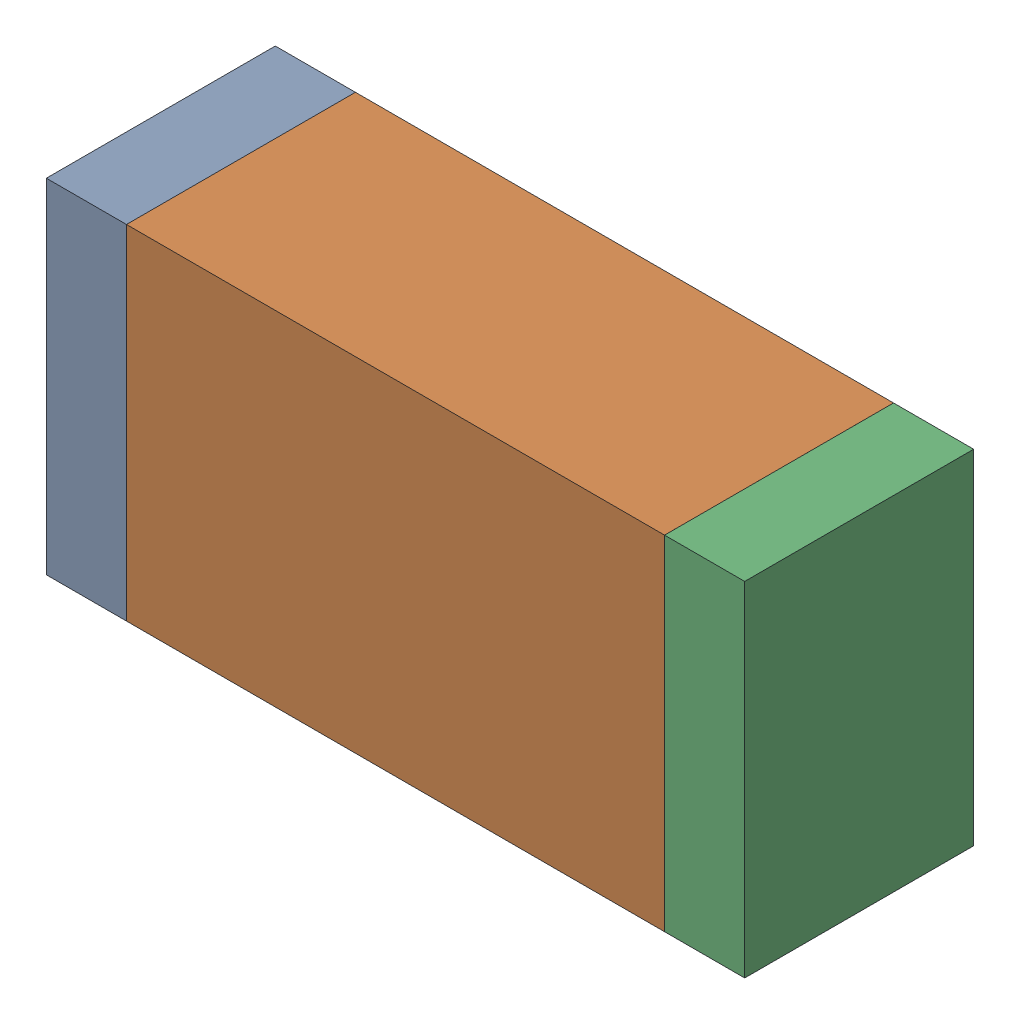
SolidWorks assembly C4, configuration Default. Lengths in mm.
Overall size (1.55 0.76 0.51).
6 component instances, 2 part files, 0 mates.
Components (placement in the parent):
- 822490216-1: 822490216 [Default] at (6.2603 2.7083 0) size (0.18 0.76 0.51)
  - Extruded-1: Extruded [Default] at origin size (0.18 0.76 0.51)
- 822498920-1: 822498920 [Default] at (6.9461 2.7083 0) size (1.19 0.76 0.51)
  - Extruded_2-1: Extruded_2 [Default] at origin size (1.19 0.76 0.51)
- 822490216-2: 822490216 [Default] at (7.6319 2.7083 0) size (0.18 0.76 0.51)
  - Extruded-1: Extruded [Default] at origin size (0.18 0.76 0.51)
